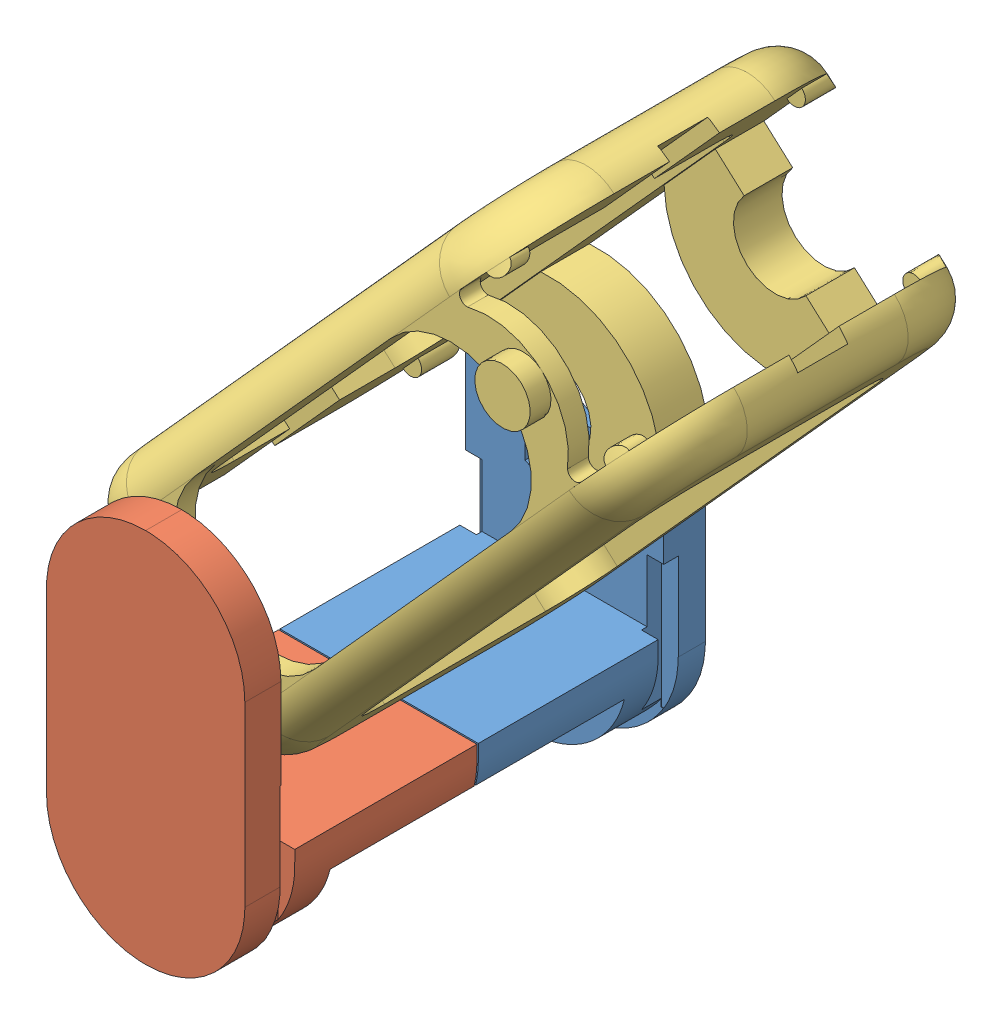
SolidWorks assembly Assem_arm_hand_colision, configuration Default. Lengths in mm.
Overall size (45.15 57.12 33.2).
3 component instances, 3 part files, 5 mates.
Components (placement in the parent):
- servo_bracket_elbow_main-1: servo_bracket_elbow_main [ﾃﾞﾌｫﾙﾄ] at (63.1703 8.8653 20.4638) size (14.4 27.1 16.38)
- servo_bracket_elbow_sub-1: servo_bracket_elbow_sub [ﾃﾞﾌｫﾙﾄ] at (63.1703 8.8653 20.4638) size (14.4 27.1 16.74)
- servo_assem_type1-1: servo_assem_type1 [ﾃﾞﾌｫﾙﾄ] at (45.8451 57.3449 9.5138) x (-0.669639 -0.742687 0) z (0 0 1) size (47.9 17.6 27.3)
Mates (geometry in assembly coordinates):
- 同心円1: concentric anti-aligned: cylinder of servo_bracket_elbow_main-1 through (17.5194 25.9293 1.4138) axis (0 0 1) radius 2.7; cylinder of servo_bracket_elbow_sub-1 through (17.5194 25.9293 34.0138) axis (0 0 -1) radius 2
- 一致2: coincident aligned: plane of servo_bracket_elbow_main-1 through (10.5201 15.0809 11.2992) normal (0 1 0); plane of servo_bracket_elbow_sub-1 through (24.8207 15.0809 24.4476) normal (0 1 0)
- 距離1: distance = 0.1 mm anti-aligned: plane of servo_bracket_elbow_sub-1 through (10.5202 12.3653 17.8814) normal (0 0 -1); plane of servo_bracket_elbow_main-1 through (10.5202 12.3653 17.7814) normal (0 0 1)
- 同心円2: concentric aligned: cylinder of servo_bracket_elbow_sub-1 through (17.5194 25.9293 34.0138) axis (0 0 -1) radius 2; cylinder of servo_assem_type1-1 through (17.5194 25.9293 33.3138) axis (0 0 -1) radius 2
- 距離2: distance = 0.2 mm anti-aligned: plane of servo_assem_type1-1 through (47.6263 46.179 31.8138) normal (0 0 1); plane of servo_bracket_elbow_sub-1 through (22.7254 9.0102 32.0138) normal (0 0 -1)
